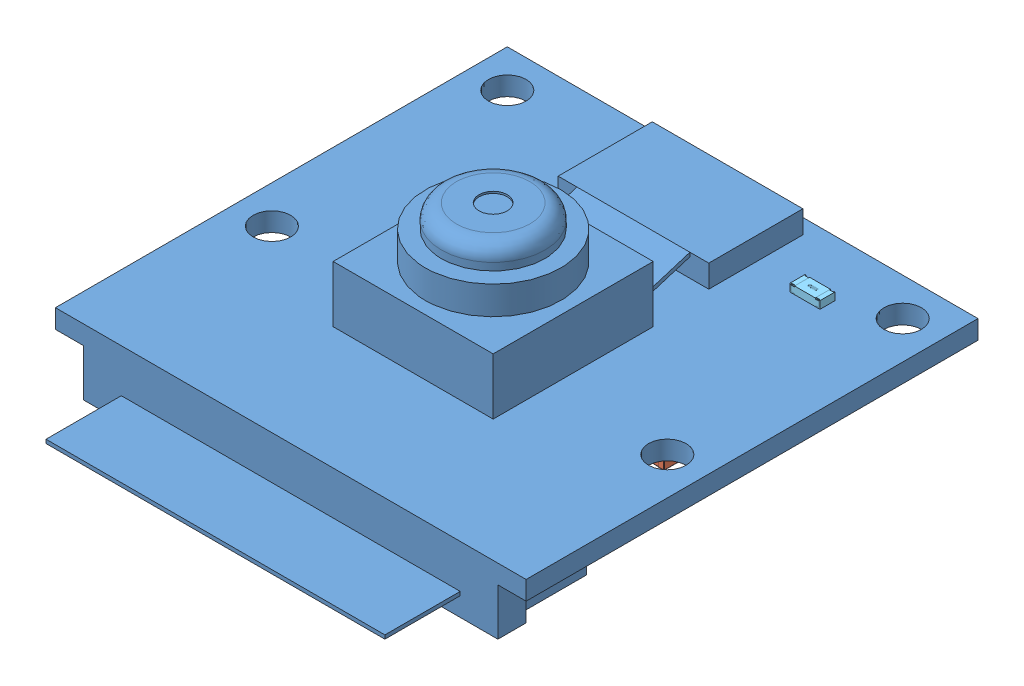
SolidWorks assembly 摄像头, configuration 默认. Lengths in mm.
Overall size (25 9.2 28).
64 component instances, 5 part files, 20 mates.
Components (placement in the parent):
- 摄像头-1: 摄像头 [默认] at origin size (25 9.2 28)
- 0603电容-2: 0603电容 [默认] at (-25.6955 -0.01 -49.0268) x (1 0 0) z (0 -1 0) size (1.6 0.82 0.82)
  - C_0603^0603电容-1: C_0603^0603电容 [默认] at (34.005 43.815 0) x (-1 0 0) z (0 0 1) size (1.6 0.82 0.82) (virtual)
    - C_0603-9^C_0603_0603电容-1: C_0603-9^C_0603_0603电容 [默认] at origin size (1.6 0.82 0.82) (virtual)
- 0603电容-3: 0603电容 [默认] at (-42.3062 -0.01 -47.0667) x (1 0 0) z (0 -1 0) size (1.6 0.82 0.82)
  - C_0603^0603电容-1: C_0603^0603电容 [默认] at (34.005 43.815 0) x (-1 0 0) z (0 0 1) size (1.6 0.82 0.82) (virtual)
    - C_0603-9^C_0603_0603电容-1: C_0603-9^C_0603_0603电容 [默认] at origin size (1.6 0.82 0.82) (virtual)
- 0603电容-7: 0603电容 [默认] at (49.2456 -0.01 -38.1328) x (0 0 1) z (0 -1 0) size (1.6 0.82 0.82)
  - C_0603^0603电容-1: C_0603^0603电容 [默认] at (34.005 43.815 0) x (-1 0 0) z (0 0 1) size (1.6 0.82 0.82) (virtual)
    - C_0603-9^C_0603_0603电容-1: C_0603-9^C_0603_0603电容 [默认] at origin size (1.6 0.82 0.82) (virtual)
- 0603电容-10: 0603电容 [默认] at (-25.4606 -0.01 -42.7048) x (1 0 0) z (0 -1 0) size (1.6 0.82 0.82)
  - C_0603^0603电容-1: C_0603^0603电容 [默认] at (34.005 43.815 0) x (-1 0 0) z (0 0 1) size (1.6 0.82 0.82) (virtual)
    - C_0603-9^C_0603_0603电容-1: C_0603-9^C_0603_0603电容 [默认] at origin size (1.6 0.82 0.82) (virtual)
- 0603电容-12: 0603电容 [默认] at (-26.2671 -0.01 -53.9256) x (1 0 0) z (0 -1 0) size (1.6 0.82 0.82)
  - C_0603^0603电容-1: C_0603^0603电容 [默认] at (34.005 43.815 0) x (-1 0 0) z (0 0 1) size (1.6 0.82 0.82) (virtual)
    - C_0603-9^C_0603_0603电容-1: C_0603-9^C_0603_0603电容 [默认] at origin size (1.6 0.82 0.82) (virtual)
- 0805电容-1: 0805电容 [默认] at (51.4431 -0.01 78.819) x (-1 0 0) z (0 -1 0) size (1.22 2 0.52)
  - C_0805^0805电容-1: C_0805^0805电容 [默认] at (59.563 77.597 0) x (0 1 0) z (0 0 1) size (2 1.22 0.52) (virtual)
    - C_0805-5^C_0805_0805电容-1: C_0805-5^C_0805_0805电容 [默认] at origin size (2 1.22 0.52) (virtual)
- 0805电阻-1: 0805电阻 [默认] at (115.7364 0 -119.6397) x (0 0 1) z (0 -1 0) size (1.25 2 0.5)
  - R_0805^0805电阻-1: R_0805^0805电阻 [默认] at (112.776 107.442 0) x (0 1 0) z (0 0 1) size (2 1.25 0.5) (virtual)
    - R_0805-21^R_0805_0805电阻-1: R_0805-21^R_0805_0805电阻 [默认] at origin size (2 1.25 0.5) (virtual)
- 0603电阻-3: 0603电阻 [默认] at (118.0517 0 -149.4378) x (0 0 1) z (0 -1 0) size (0.8 1.6 0.4)
  - R_0603^0603电阻-1: R_0603^0603电阻 [默认] at (138.684 113.411 0) x (0 1 0) z (0 0 1) size (1.6 0.8 0.4) (virtual)
    - R_0603-25^R_0603_0603电阻-1: R_0603-25^R_0603_0603电阻 [默认] at origin size (1.6 0.8 0.4) (virtual)
- 0603电阻-4: 0603电阻 [默认] at (-106.3314 1 -147.3108) x (0 0 1) z (0 1 0) size (0.8 1.6 0.4)
  - R_0603^0603电阻-1: R_0603^0603电阻 [默认] at (138.684 113.411 0) x (0 1 0) z (0 0 1) size (1.6 0.8 0.4) (virtual)
    - R_0603-25^R_0603_0603电阻-1: R_0603-25^R_0603_0603电阻 [默认] at origin size (1.6 0.8 0.4) (virtual)
- 0603电阻-5: 0603电阻 [默认] at (134.1937 0 114.6319) x (-1 0 0) z (0 -1 0) size (0.8 1.6 0.4)
  - R_0603^0603电阻-1: R_0603^0603电阻 [默认] at (138.684 113.411 0) x (0 1 0) z (0 0 1) size (1.6 0.8 0.4) (virtual)
    - R_0603-25^R_0603_0603电阻-1: R_0603-25^R_0603_0603电阻 [默认] at origin size (1.6 0.8 0.4) (virtual)
- 0603电容-14: 0603电容 [默认] at (-26.2671 -0.01 -52.4256) x (1 0 0) z (0 -1 0) size (1.6 0.82 0.82)
  - C_0603^0603电容-1: C_0603^0603电容 [默认] at (34.005 43.815 0) x (-1 0 0) z (0 0 1) size (1.6 0.82 0.82) (virtual)
    - C_0603-9^C_0603_0603电容-1: C_0603-9^C_0603_0603电容 [默认] at origin size (1.6 0.82 0.82) (virtual)
- 0603电容-15: 0603电容 [默认] at (-30.4606 -0.01 -42.7048) x (1 0 0) z (0 -1 0) size (1.6 0.82 0.82)
  - C_0603^0603电容-1: C_0603^0603电容 [默认] at (34.005 43.815 0) x (-1 0 0) z (0 0 1) size (1.6 0.82 0.82) (virtual)
    - C_0603-9^C_0603_0603电容-1: C_0603-9^C_0603_0603电容 [默认] at origin size (1.6 0.82 0.82) (virtual)
- 0603电容-16: 0603电容 [默认] at (-35.4606 -0.01 -42.7048) x (1 0 0) z (0 -1 0) size (1.6 0.82 0.82)
  - C_0603^0603电容-1: C_0603^0603电容 [默认] at (34.005 43.815 0) x (-1 0 0) z (0 0 1) size (1.6 0.82 0.82) (virtual)
    - C_0603-9^C_0603_0603电容-1: C_0603-9^C_0603_0603电容 [默认] at origin size (1.6 0.82 0.82) (virtual)
- 0603电容-17: 0603电容 [默认] at (-37.2671 -0.01 -53.9256) x (1 0 0) z (0 -1 0) size (1.6 0.82 0.82)
  - C_0603^0603电容-1: C_0603^0603电容 [默认] at (34.005 43.815 0) x (-1 0 0) z (0 0 1) size (1.6 0.82 0.82) (virtual)
    - C_0603-9^C_0603_0603电容-1: C_0603-9^C_0603_0603电容 [默认] at origin size (1.6 0.82 0.82) (virtual)
- 0603电容-18: 0603电容 [默认] at (-37.2671 -0.01 -52.4256) x (1 0 0) z (0 -1 0) size (1.6 0.82 0.82)
  - C_0603^0603电容-1: C_0603^0603电容 [默认] at (34.005 43.815 0) x (-1 0 0) z (0 0 1) size (1.6 0.82 0.82) (virtual)
    - C_0603-9^C_0603_0603电容-1: C_0603-9^C_0603_0603电容 [默认] at origin size (1.6 0.82 0.82) (virtual)
- 0805电阻-2: 0805电阻 [默认] at (104.7364 0 -119.6397) x (0 0 1) z (0 -1 0) size (1.25 2 0.5)
  - R_0805^0805电阻-1: R_0805^0805电阻 [默认] at (112.776 107.442 0) x (0 1 0) z (0 0 1) size (2 1.25 0.5) (virtual)
    - R_0805-21^R_0805_0805电阻-1: R_0805-21^R_0805_0805电阻 [默认] at origin size (2 1.25 0.5) (virtual)
- 0603电容-19: 0603电容 [默认] at (-31.1955 -0.01 -49.0268) x (1 0 0) z (0 -1 0) size (1.6 0.82 0.82)
  - C_0603^0603电容-1: C_0603^0603电容 [默认] at (34.005 43.815 0) x (-1 0 0) z (0 0 1) size (1.6 0.82 0.82) (virtual)
    - C_0603-9^C_0603_0603电容-1: C_0603-9^C_0603_0603电容 [默认] at origin size (1.6 0.82 0.82) (virtual)
- 0603电容-20: 0603电容 [默认] at (-36.6955 -0.01 -49.0268) x (1 0 0) z (0 -1 0) size (1.6 0.82 0.82)
  - C_0603^0603电容-1: C_0603^0603电容 [默认] at (34.005 43.815 0) x (-1 0 0) z (0 0 1) size (1.6 0.82 0.82) (virtual)
    - C_0603-9^C_0603_0603电容-1: C_0603-9^C_0603_0603电容 [默认] at origin size (1.6 0.82 0.82) (virtual)
- 0603电容-21: 0603电容 [默认] at (43.7456 -0.01 -38.1328) x (0 0 1) z (0 -1 0) size (1.6 0.82 0.82)
  - C_0603^0603电容-1: C_0603^0603电容 [默认] at (34.005 43.815 0) x (-1 0 0) z (0 0 1) size (1.6 0.82 0.82) (virtual)
    - C_0603-9^C_0603_0603电容-1: C_0603-9^C_0603_0603电容 [默认] at origin size (1.6 0.82 0.82) (virtual)
- 0603电容-22: 0603电容 [默认] at (38.2456 -0.01 -38.1328) x (0 0 1) z (0 -1 0) size (1.6 0.82 0.82)
  - C_0603^0603电容-1: C_0603^0603电容 [默认] at (34.005 43.815 0) x (-1 0 0) z (0 0 1) size (1.6 0.82 0.82) (virtual)
    - C_0603-9^C_0603_0603电容-1: C_0603-9^C_0603_0603电容 [默认] at origin size (1.6 0.82 0.82) (virtual)
- 0603电阻-6: 0603电阻 [默认] at (132.6937 0 114.6319) x (-1 0 0) z (0 -1 0) size (0.8 1.6 0.4)
  - R_0603^0603电阻-1: R_0603^0603电阻 [默认] at (138.684 113.411 0) x (0 1 0) z (0 0 1) size (1.6 0.8 0.4) (virtual)
    - R_0603-25^R_0603_0603电阻-1: R_0603-25^R_0603_0603电阻 [默认] at origin size (1.6 0.8 0.4) (virtual)
Mates (geometry in assembly coordinates):
- 重合45: coincident anti-aligned: plane of 摄像头-1 through (0 0 0) normal (0 -1 0); plane of 0603电容-12/C_0603^0603电容-1/C_0603-9^C_0603_0603电容-1 through (8.5379 0 -10.5206) normal (0 1 0)
- 平行23: parallel aligned: plane of 摄像头-1 through (12.5 1 12) normal (1 0 0); plane of 0603电容-12/C_0603^0603电容-1/C_0603-9^C_0603_0603电容-1 through (8.5379 -0.01 -10.1105) normal (1 0 0)
- 重合47: coincident anti-aligned: plane of 摄像头-1 through (0 0 0) normal (0 -1 0); plane of 0603电容-2/C_0603^0603电容-1/C_0603-9^C_0603_0603电容-1 through (9.1095 0 -5.6217) normal (0 1 0)
- 平行24: parallel aligned: plane of 摄像头-1 through (12.5 1 12) normal (1 0 0); plane of 0603电容-2/C_0603^0603电容-1/C_0603-9^C_0603_0603电容-1 through (9.1095 -0.01 -5.2117) normal (1 0 0)
- 重合49: coincident anti-aligned: plane of 摄像头-1 through (0 0 0) normal (0 -1 0); plane of 0603电容-3/C_0603^0603电容-1/C_0603-9^C_0603_0603电容-1 through (-7.5012 0 -3.6617) normal (0 1 0)
- 平行25: parallel aligned: plane of 摄像头-1 through (12.5 1 12) normal (1 0 0); plane of 0603电容-3/C_0603^0603电容-1/C_0603-9^C_0603_0603电容-1 through (-7.5012 -0.01 -3.2517) normal (1 0 0)
- 重合55: coincident anti-aligned: plane of 摄像头-1 through (0 0 0) normal (0 -1 0); plane of 0603电容-10/C_0603^0603电容-1/C_0603-9^C_0603_0603电容-1 through (9.3444 0 0.7002) normal (0 1 0)
- 平行28: parallel aligned: plane of 摄像头-1 through (12.5 1 12) normal (1 0 0); plane of 0603电容-10/C_0603^0603电容-1/C_0603-9^C_0603_0603电容-1 through (9.3444 -0.01 1.1102) normal (1 0 0)
- 重合57: coincident anti-aligned: plane of 摄像头-1 through (0 0 0) normal (0 -1 0); plane of 0805电阻-1/R_0805^0805电阻-1/R_0805-21^R_0805_0805电阻-1 through (7.5944 0 -6.2387) normal (0 1 0)
- 平行29: parallel aligned: plane of 摄像头-1 through (12.5 1 -12) normal (0 0 -1); plane of 0805电阻-1/R_0805^0805电阻-1/R_0805-21^R_0805_0805电阻-1 through (9.2944 -0.5 -7.4887) normal (0 0 -1)
- 重合59: coincident anti-aligned: plane of 摄像头-1 through (0 0 0) normal (0 -1 0); plane of 0603电容-7/C_0603^0603电容-1/C_0603-9^C_0603_0603电容-1 through (5.8406 0 -3.3278) normal (0 1 0)
- 平行30: parallel anti-aligned: plane of 摄像头-1 through (12.5 1 12) normal (1 0 0); plane of 0603电容-7/C_0603^0603电容-1/C_0603-9^C_0603_0603电容-1 through (5.0306 -0.81 -3.6278) normal (-1 0 0)
- 重合61: coincident anti-aligned: plane of 摄像头-1 through (0 0 0) normal (0 -1 0); plane of 0603电阻-3/R_0603^0603电阻-1/R_0603-25^R_0603_0603电阻-1 through (5.1907 0 -10.3538) normal (0 1 0)
- 重合62: coincident anti-aligned: plane of 摄像头-1 through (0 0 0) normal (0 -1 0); plane of 0603电阻-5/R_0603^0603电阻-1/R_0603-25^R_0603_0603电阻-1 through (-4.8903 0 1.7709) normal (0 1 0)
- 平行31: parallel aligned: plane of 摄像头-1 through (12.5 1 -12) normal (0 0 -1); plane of 0603电阻-3/R_0603^0603电阻-1/R_0603-25^R_0603_0603电阻-1 through (5.4407 -0.4 -11.1538) normal (0 0 -1)
- 平行32: parallel anti-aligned: plane of 摄像头-1 through (12.5 1 12) normal (1 0 0); plane of 0603电阻-5/R_0603^0603电阻-1/R_0603-25^R_0603_0603电阻-1 through (-4.8903 -0.4 2.0209) normal (-1 0 0)
- 重合65: coincident anti-aligned: plane of 摄像头-1 through (0 0 0) normal (0 -1 0); plane of 0805电容-1/C_0805^0805电容-1/C_0805-5^C_0805_0805电容-1 through (-7.5099 0 2.222) normal (0 1 0)
- 平行33: parallel anti-aligned: plane of 摄像头-1 through (-12.5 1 12) normal (-1 0 0); plane of 0805电容-1/C_0805^0805电容-1/C_0805-5^C_0805_0805电容-1 through (-7.5199 -0.51 1.922) normal (1 0 0)
- 重合67: coincident anti-aligned: plane of 摄像头-1 through (0 1 0) normal (0 1 0); plane of 0603电阻-4/R_0603^0603电阻-1/R_0603-25^R_0603_0603电阻-1 through (7.6296 1 -8.2268) normal (0 -1 0)
- 平行36: parallel anti-aligned: plane of 摄像头-1 through (12.5 1 -12) normal (0 0 -1); plane of 0603电阻-4/R_0603^0603电阻-1/R_0603-25^R_0603_0603电阻-1 through (6.2796 1.4 -8.2268) normal (0 0 1)
